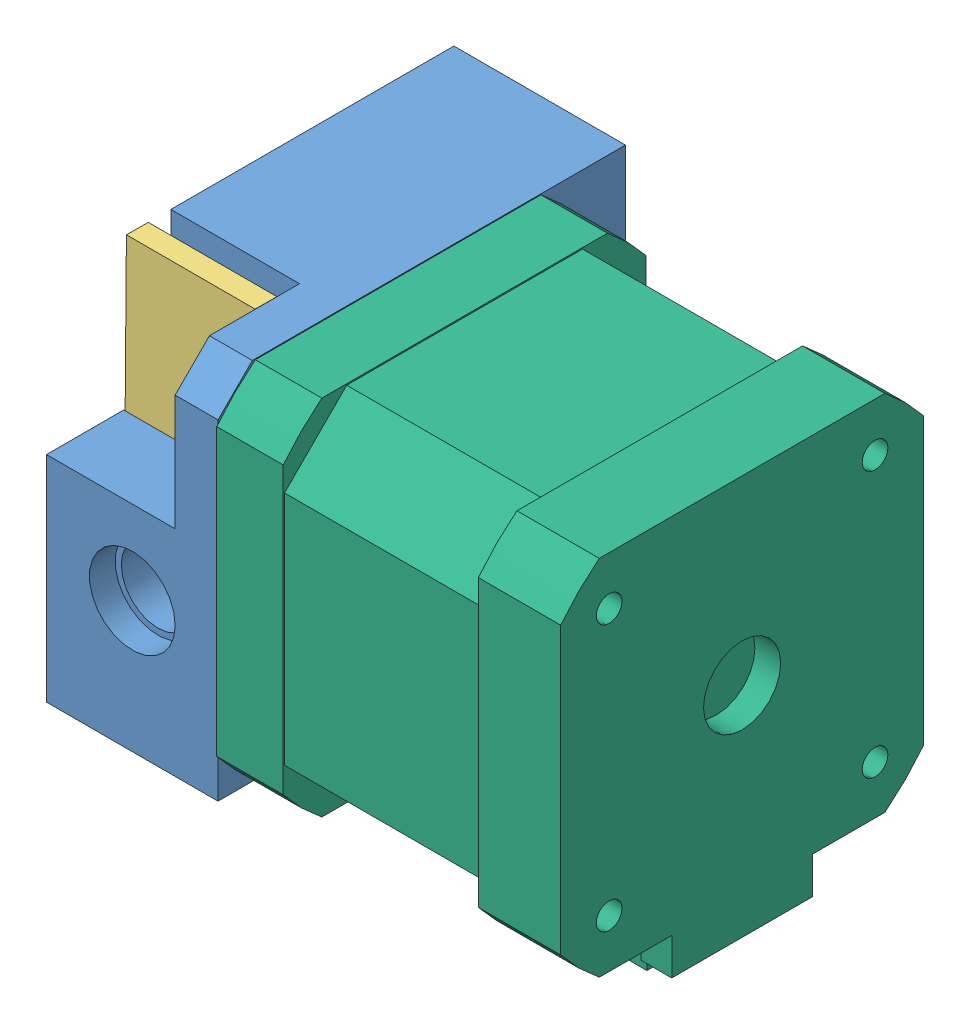
SolidWorks assembly SubEnsamblaje_CuerpoExtrusor_BQ, configuration Predeterminado. Lengths in mm.
Overall size (60.1 48.13 47.65).
10 component instances, 9 part files, 20 mates.
Components (placement in the parent):
- extruder-body-part-1: extruder-body-part [Predeterminado] at (0.4154 8.1053 -127.88) size (20 45 47.5)
- lever-shaft-final-1: lever-shaft-final [Predeterminado] at (0.4154 8.1053 -127.88) size (20 3 3)
- extruder-lever-final-1: extruder-lever-final [Predeterminado] at (0.4154 6.5726 -128.1067) x (1 0 0) z (0 0.00823 0.999966) size (15 42.5 16)
- Extruder-lever-623zz-bearing-1: Extruder-lever-623zz-bearing [Predeterminado] at (0.1654 -10.2804 -129.3004) x (1 0 0) z (0 0.102182 0.994766) size (4 10 10)
- ISO-10642-M3x12-bolt-1-2: ISO-10642-M3x12-bolt-1 [Predeterminado] at (0.1654 6.5726 -128.1067) x (1 0 0) z (0 0.00823 0.999966) size (12.11 6.05 6.05)
- Extruder-motor-Nema-17-40mm-with-connector-2: Extruder-motor-Nema-17-40mm-with-connector [Predeterminado] at (0.4154 8.1053 -127.88) size (60.1 48 42.3)
- Extruder-drive-gear-2: Extruder-drive-gear [Predeterminado] at (0.4154 8.1053 -127.88) size (11 12.5 12.5)
- extruder-setscrew2-1: extruder-setscrew2 [Predeterminado] at (4.4154 -142.59 40.1847) x (1 0 0) z (0 1 0) size (3 3 3)
- socket head cap screw_iso-3: socket head cap screw_iso [ISO 4762 M3 x 20 --- 20N] at (-9.4012 12.54 34.75) size (23 5.5 5.5)
- socket head cap screw_iso-4: socket head cap screw_iso [ISO 4762 M3 x 20 --- 20N] at (-9.4012 -18.46 34.75) size (23 5.5 5.5)
Mates (geometry in assembly coordinates):
- Bloquear1: lock: unknown of extruder-body-part-1; unknown of lever-shaft-final-1
- Coincidente3: coincident aligned: plane of extruder-body-part-1 through (10.1988 -26.7083 23.75) normal (1 0 0); plane of lever-shaft-final-1 through (10.1988 -20.21 58.25) normal (1 0 0)
- Concéntrica5: concentric anti-aligned: cylinder of lever-shaft-final-1 through (-9.3012 -20.21 58.25) axis (1 0 0) radius 1.5; cylinder of extruder-lever-final-1 through (-9.8012 -20.21 58.25) axis (-1 0 0) radius 1.5
- Bloquear2: lock: unknown of extruder-lever-final-1; unknown of ISO-10642-M3x12-bolt-1-2
- Coincidente4: coincident aligned: plane of extruder-lever-final-1 through (5.1988 -24.2024 58.0036) normal (1 0 0); plane of ISO-10642-M3x12-bolt-1-2 through (5.1988 -14.526 50.203) normal (1 0 0)
- Concéntrica12: concentric aligned: cylinder of Extruder-lever-623zz-bearing-1 through (-1.8012 -14.526 50.203) axis (-1 0 0) radius 1.5; cylinder of ISO-10642-M3x12-bolt-1-2 through (3.4988 -14.526 50.203) axis (-1 0 0) radius 1.5
- Ancho1: width aligned: plane of Extruder-lever-623zz-bearing-1 through (-1.8012 -9.5522 49.692) normal (-1 0 0); plane of Extruder-lever-623zz-bearing-1 through (2.1988 -9.5522 49.692) normal (1 0 0); plane of extruder-lever-final-1 through (2.4488 -29.5584 46.3265) normal (-1 0 0); plane of extruder-lever-final-1 through (-2.0512 0.4406 46.0796) normal (1 0 0)
- Coincidente5: coincident anti-aligned: plane of extruder-body-part-1 through (5.1988 -24.2083 44.25) normal (-1 0 0); plane of extruder-lever-final-1 through (5.1988 -24.2024 58.0036) normal (1 0 0)
- Concéntrica15: concentric anti-aligned: cylinder of Extruder-drive-gear-2 through (4.1988 -2.96 50.25) axis (0 1 0) radius 1.25; cylinder of extruder-setscrew2-1 through (4.1988 2.04 50.25) axis (0 -1 0) radius 1.5
- Coincidente8: coincident anti-aligned: plane of Extruder-motor-Nema-17-40mm-with-connector-2 through (-9.8012 -0.96 51.75) normal (0 1 0); plane of extruder-setscrew2-1 through (4.1988 -0.96 50.25) normal (0 -1 0)
- Concéntrica16: concentric anti-aligned: cylinder of Extruder-motor-Nema-17-40mm-with-connector-2 through (10.1988 -2.96 50.25) axis (1 0 0) radius 2.5; cylinder of Extruder-drive-gear-2 through (7.1988 -2.96 50.25) axis (-1 0 0) radius 2.5
- Distancia1: distance = 1 mm anti-aligned: plane of Extruder-drive-gear-2 through (7.1988 -2.96 50.25) normal (1 0 0); plane of Extruder-motor-Nema-17-40mm-with-connector-2 through (8.1988 -13.96 50.25) normal (-1 0 0)
- Paralelo15: parallel aligned: plane of extruder-body-part-1 through (10.1988 -26.7083 23.75) normal (0 0 -1); plane of Extruder-motor-Nema-17-40mm-with-connector-2 through (50.2988 13.69 29.1) normal (0 0 -1)
- Concéntrica25: concentric anti-aligned: circle of extruder-body-part-1; cylinder of Extruder-motor-Nema-17-40mm-with-connector-2 through (10.1988 12.54 34.75) axis (-1 0 0) radius 1.225
- Concéntrica26: concentric anti-aligned: cylinder of extruder-body-part-1 through (10.1988 -18.46 34.75) axis (1 0 0) radius 1.75; cylinder of Extruder-motor-Nema-17-40mm-with-connector-2 through (10.1988 -18.46 34.75) axis (-1 0 0) radius 1.225
- Coincidente24: coincident anti-aligned: plane of extruder-body-part-1 through (10.1988 -26.7083 23.75) normal (1 0 0); plane of Extruder-motor-Nema-17-40mm-with-connector-2 through (10.1988 13.69 29.1) normal (-1 0 0)
- Concéntrica27: concentric anti-aligned: cylinder of extruder-body-part-1 through (10.1988 12.54 34.75) axis (1 0 0) radius 1.75; cylinder of socket head cap screw_iso-3 through (-41.1512 12.54 34.75) axis (-1 0 0) radius 2.75
- Coincidente25: coincident anti-aligned: plane of extruder-body-part-1 through (-6.4012 9.29 34.75) normal (-1 0 0); plane of socket head cap screw_iso-3 through (-6.4012 15.29 34.75) normal (1 0 0)
- Concéntrica28: concentric anti-aligned: cylinder of extruder-body-part-1 through (10.1988 -18.46 34.75) axis (1 0 0) radius 1.75; cylinder of socket head cap screw_iso-4 through (-41.1512 -18.46 34.75) axis (-1 0 0) radius 2.75
- Coincidente26: coincident anti-aligned: plane of extruder-body-part-1 through (-6.4012 -21.71 34.75) normal (-1 0 0); plane of socket head cap screw_iso-4 through (-6.4012 -15.71 34.75) normal (1 0 0)
